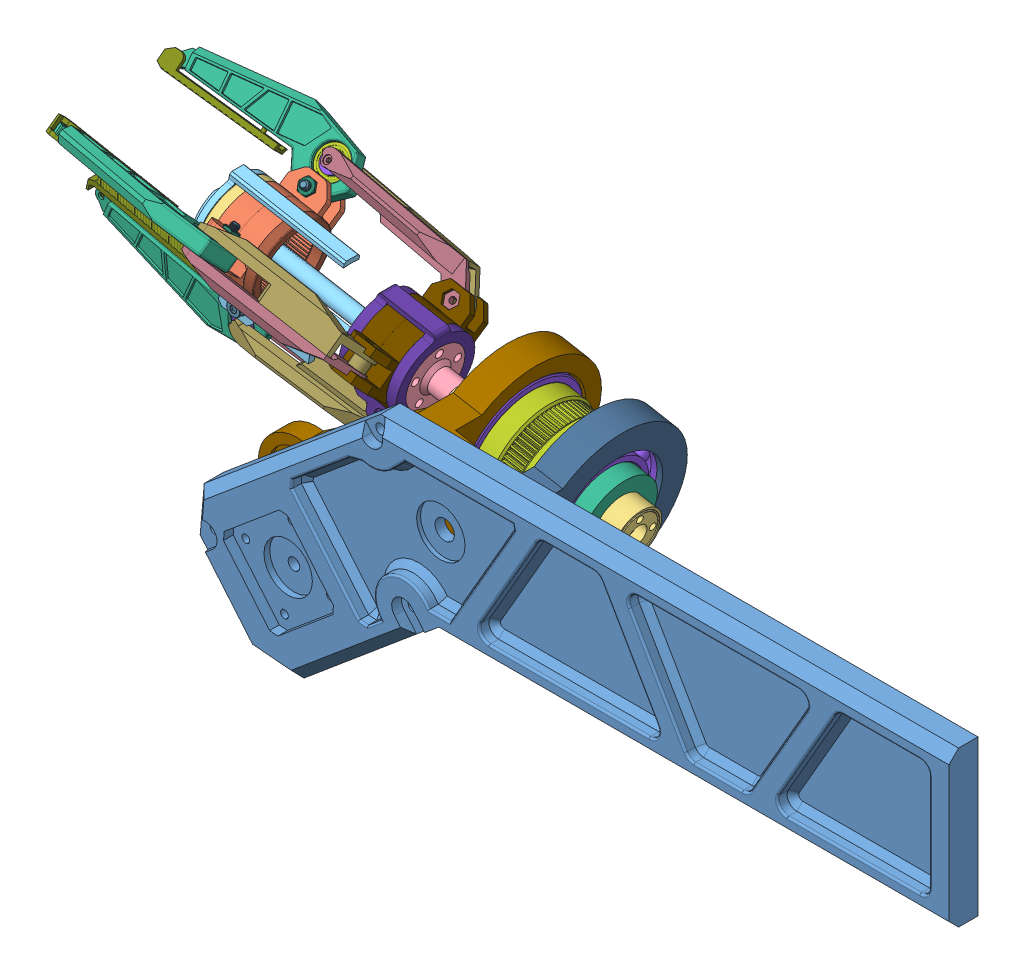
SolidWorks assembly AJ1, configuration Default. Lengths in mm.
Overall size (510.26 191.88 118.53).
61 component instances, 30 part files, 5 mates.
Components (placement in the parent):
- UpperSec-1: UpperSec [Default] at (34.476 163.0285 299.7549) size (391.25 137.61 15.09)
- CrawAssemV1.2-1: CrawAssemV1.2 [EX2] at (-53.1663 200.1756 226.5593) x (0.002865 0.01582 0.999871) z (-0.984 0.178167 0) size (105.21 107.56 278.95)
  - CrawPivotL-1: CrawPivotL [Default] at (23.6534 28.2906 36.4169) x (0.675201 -0.737634 0) z (0 0 1) size (40 51.64 20.02)
  - RotorInner-1: RotorInner [Default] at (23.6534 28.2906 51.4169) x (-0.675201 0.737634 0) z (0 0 -1) size (40 40 22.5)
  - 4668K131_Permanently Lubricated Stainless Steel Ball Bearing-1: 4668K131_Permanently Lubricated Stainless Steel Ball Bearing [4668K131] at (23.6534 28.2906 52.4169) x (0.977927 0.208948 0) z (0 0 1) size (16 16 4)
  - RotorOutter-1: RotorOutter [Default] at (23.6534 28.2906 56.4169) x (-0.999871 0.016078 0) z (0 0 -1) size (40 57.1 62)
  - CrawPivotL-2: CrawPivotL [Default] at (23.6534 28.2906 36.4169) x (-0.716673 -0.697409 0) z (0 0 -1) size (40 51.64 20.02)
  - FrontCraw-1: FrontCraw [Default] at (-7.9204 40.6623 113.525) x (-0.024761 0.025445 -0.99937) z (0.69697 -0.716221 -0.035504) size (92.48 8.06 30.71)
  - FrontCraw-2: FrontCraw [Default] at (49.7643 43.7862 113.4714) x (0.035168 0.032192 -0.998863) z (-0.736795 -0.674433 -0.047677) size (92.48 8.06 30.71)
  - 4668K334_Permanently Lubricated Stainless Steel Ball Bearing-1: 4668K334_Permanently Lubricated Stainless Steel Ball Bearing [4668K334] at (58.2277 46.2461 36.989) x (0.461728 0.422648 0.779857) z (-0.675201 0.737634 0) size (16 16 5)
  - BearingStop1-1: BearingStop1 [Default] at (56.5397 48.0902 36.989) x (-0.727461 -0.665889 0.165503) z (0.675201 -0.737634 0) size (10 10 6.25)
  - 4668K334_Permanently Lubricated Stainless Steel Ball Bearing-2: 4668K334_Permanently Lubricated Stainless Steel Ball Bearing [4668K334] at (-9.9873 48.3784 36.952) x (0.471273 -0.484291 0.737132) z (-0.716673 -0.697409 0) size (16 16 5)
  - BearingStop1-2: BearingStop1 [Default] at (-11.779 46.6349 36.952) x (-0.683695 0.702579 -0.197341) z (0.716673 0.697409 0) size (10 10 6.25)
  - BearingStop2-1: BearingStop2 [Default] at (55.6957 49.0123 36.989) x (-0.727461 -0.665889 0.165503) z (0.675201 -0.737634 0) size (10 10 7.25)
  - BearingStop2-2: BearingStop2 [Default] at (-12.6749 45.7632 36.952) x (-0.683695 0.702579 -0.197341) z (0.716673 0.697409 0) size (10 10 7.25)
  - FrontCraw-3: FrontCraw [Default] at (27.1452 -3.3521 113.4714) x (-0.000767 -0.047671 -0.998863) z (0.016059 0.998734 -0.047677) size (92.48 8.06 30.71)
  - 7804K117_Stainless Steel Ball Bearing-1: 7804K117_Stainless Steel Ball Bearing [7804K117] at (23.1186 -11.1922 36.989) x (-0.007051 -0.438494 -0.898707) z (0.999871 -0.016078 0) size (16 16 5)
  - BearingStop2-3: BearingStop2 [Default] at (19.3691 -11.1319 36.989) x (0.016038 0.997394 0.070343) z (0.999871 -0.016078 0) size (10 10 7.25)
  - BearingStop1-3: BearingStop1 [Default] at (20.6189 -11.152 36.989) x (0.016038 0.997394 0.070343) z (0.999871 -0.016078 0) size (10 10 6.25)
  - RotorInnerBack-1: RotorInnerBack [Default] at (23.6534 28.2906 21.4169) x (0.962311 -0.271952 0) z (0 0 1) size (40 40 8)
  - SEC2pull1-1: SEC2pull1 [Default] at (-10.6231 40.787 37.118) x (0.023165 -0.023805 -0.999448) z (0.716673 0.697409 0) size (85.51 19.7 15)
  - SEC2pull2-1: SEC2pull2 [Default] at (-3.4564 47.7611 37.118) x (0.023165 -0.023805 -0.999448) z (0.716673 0.697409 0) size (85.51 19.7 8.5)
  - 91290A164_Black-Oxide Alloy Steel Socket Head Screw-1: 91290A164_Black-Oxide Alloy Steel Socket Head Screw [91290A164] at (23.2113 0.7942 36.4169) x (0.000258 0.016076 -0.999871) z (0.999871 -0.016078 0) size (7 7 22.3)
  - 90592A090_Steel Hex Nut (1)-1: 90592A090_Steel Hex Nut (1) [90592A090] at (14.6124 0.9324 36.4169) x (0.016078 0.999871 0) z (0 0 1) size (7 3.75 8.08)
  - 91290A164_Black-Oxide Alloy Steel Socket Head Screw-2: 91290A164_Black-Oxide Alloy Steel Socket Head Screw [91290A164] at (-0.6785 40.3897 36.4169) x (-0.0003 0.000308 -1) z (-0.716673 -0.697409 0) size (7 7 22.3)
  - 90592A090_Steel Hex Nut (1)-2: 90592A090_Steel Hex Nut (1) [90592A090] at (4.0516 44.9926 36.4169) x (-0.348705 0.358336 -0.866025) z (-0.603974 0.620657 0.5) size (7 3.75 8.08)
  - 91290A164_Black-Oxide Alloy Steel Socket Head Screw-3: 91290A164_Black-Oxide Alloy Steel Socket Head Screw [91290A164] at (48.6435 38.9643 36.4169) x (-0.209995 -0.192222 0.95862) z (0.675201 -0.737634 0) size (7 7 22.3)
  - 90592A090_Steel Hex Nut (1)-3: 90592A090_Steel Hex Nut (1) [90592A090] at (44.1872 43.8327 36.4169) x (-0.368817 -0.3376 -0.866025) z (-0.63881 -0.584741 0.5) size (7 3.75 8.08)
  - UpperSecCraw (1)-1: UpperSecCraw (1) [Default] at (-7.216 44.2401 113.6369) x (-0.024761 0.025445 -0.99937) z (0.716673 0.697409 0) size (60.97 9.37 8)
  - UpperSecCraw (1)-2: UpperSecCraw (1) [Default] at (24.1122 -5.3749 113.6086) x (-0.000767 -0.047671 -0.998863) z (-0.999871 0.016078 0) size (60.97 9.37 8)
  - UpperSecCraw (1)-3: UpperSecCraw (1) [Default] at (53.3178 42.9719 113.6086) x (0.035168 0.032192 -0.998863) z (0.675201 -0.737634 0) size (60.97 9.37 8)
  - RTL-1: RTL [Default] at (23.6534 28.2906 -18.4955) x (-0.999871 0.016078 0) z (0 0 -1) size (40 56.1 30)
  - PullPivot-1: PullPivot [Default] at (23.6534 28.2906 -38.4955) x (0.675201 -0.737634 0) z (0 0 1) size (40 51.64 20)
  - 5972K213_Ball Bearing-1: 5972K213_Ball Bearing [5972K213] at (23.6534 28.2906 -33.4955) size (24 24 5)
  - PullPivot2-1: PullPivot2 [Default] at (23.6534 28.2906 -38.4955) x (0.999025 -0.044147 0) z (0 0 1) size (35 35 2.74)
  - PullPivot-2: PullPivot [Default] at (23.6534 28.2906 -38.4955) x (-0.716673 -0.697409 0) z (0 0 -1) size (40 51.64 20)
  - 5972K213_Ball Bearing-2: 5972K213_Ball Bearing [5972K213] at (23.6534 28.2906 -43.4955) x (0.923728 0.383049 0) z (0 0 -1) size (24 24 5)
  - PullPivot2-2: PullPivot2 [Default] at (23.6534 28.2906 -38.4955) x (-0.716673 -0.697409 0) z (0 0 -1) size (35 35 2.74)
  - SEC2pull1-2: SEC2pull1 [Default] at (50.6589 47.1131 37.1398) x (-0.022244 -0.020361 -0.999545) z (0.675201 -0.737634 0) size (85.51 19.7 15)
  - SEC2pull1-3: SEC2pull1 [Default] at (29.1982 -6.2916 37.1398) x (0.000485 0.030152 -0.999545) z (-0.999871 0.016078 0) size (85.51 19.7 15)
  - SEC2pull2-2: SEC2pull2 [Default] at (19.5494 -6.1365 37.1398) x (0.000485 0.030152 -0.999545) z (-0.999871 0.016078 0) size (85.51 19.7 8.5)
  - SEC2pull2-3: SEC2pull2 [Default] at (57.4109 39.7367 37.1398) x (-0.022244 -0.020361 -0.999545) z (0.675201 -0.737634 0) size (85.51 19.7 8.5)
  - CylinderTube-1: CylinderTube [Default] at (23.6534 28.2906 -74.2503) x (-0.999871 0.016078 0) z (-0.016078 -0.999871 0) size (35 85 35)
  - Hydro2-1: Hydro2 [Default] at (23.6534 28.2906 -50.4955) x (-0.999871 0.016078 0) z (0 0 -1) size (30 30 73)
  - 6112K44_Linear Motion Shaft-1: 6112K44_Linear Motion Shaft [6112K44] at (23.6534 28.2906 -52.5831) x (-0.201275 -0.979535 0) z (0 0 1) size (8 8 100)
  - Cylinder40mmCover-1: Cylinder40mmCover [Default] at (23.6534 28.2906 -79.2503) x (-0.999871 0.016078 0) z (0 0 -1) size (40 40 70)
  - PiV1-1: PiV1 [Default] at (23.6534 28.2906 -129.2503) x (0.999871 -0.016078 0) z (0 0 1) size (55 55 30)
  - PiVEnclosure1-1: PiVEnclosure1 [Default] at (23.6534 28.2906 -109.2503) x (0.791208 -0.611547 0) z (0 0 1) size (75 75 13) (hidden)
  - 4668K334_Permanently Lubricated Stainless Steel Ball Bearing-3: 4668K334_Permanently Lubricated Stainless Steel Ball Bearing [4668K334] at (19.2674 62.5359 -106.7503) size (16 16 5) (hidden)
  - 4668K334_Permanently Lubricated Stainless Steel Ball Bearing-4: 4668K334_Permanently Lubricated Stainless Steel Ball Bearing [4668K334] at (-10.5918 23.9046 -106.7503) size (16 16 5) (hidden)
  - 4668K334_Permanently Lubricated Stainless Steel Ball Bearing-5: 4668K334_Permanently Lubricated Stainless Steel Ball Bearing [4668K334] at (28.0395 -5.9546 -106.7503) size (16 16 5) (hidden)
  - 4668K334_Permanently Lubricated Stainless Steel Ball Bearing-6: 4668K334_Permanently Lubricated Stainless Steel Ball Bearing [4668K334] at (57.8987 32.6767 -106.7503) size (16 16 5) (hidden)
  - 5972K249_Ball Bearing-1: 5972K249_Ball Bearing [5972K249] at (23.6534 28.2906 -93.2503) x (0.88466 0.466238 0) z (0 0 1) size (62 62 12)
  - 5972K249_Ball Bearing-2: 5972K249_Ball Bearing [5972K249] at (23.6534 28.2906 -135.2503) x (0.910111 -0.414364 0) z (0 0 1) size (62 62 12)
- PiVyAxis-1: PiVyAxis [Default] at (137.0869 121.2307 219.8994) x (0 0 1) z (-0.984 0.178167 0) size (90 95.96 126.21)
  - PiVRing-1: PiVRing [Default] at (-10.1445 32.4522 102.0243) size (90 95.96 109.96)
  - 5972K249_Ball Bearing-1: 5972K249_Ball Bearing [5972K249] at (29.8555 72.4522 108.2243) x (0.455975 -0.889993 0) z (0 0 1) size (62 62 12) (hidden)
  - PiVRing2-1: PiVRing2 [Default] at (69.8555 32.4522 72.0243) x (-1 0 0) z (0 0 -1) size (90 80 20.25)
  - 92010A328_Passivated 18-8 Stainless Steel Phillips Flat Head Screw-1: 92010A328_Passivated 18-8 Stainless Steel Phillips Flat Head Screw [92010A328] at (74.8555 87.4522 67.6243) x (0.998285 -0.05854 0) z (0 0 -1) size (9.2 9.2 20.12)
  - 92010A328_Passivated 18-8 Stainless Steel Phillips Flat Head Screw-2: 92010A328_Passivated 18-8 Stainless Steel Phillips Flat Head Screw [92010A328] at (74.8555 57.4522 67.6243) x (1 0 0) z (0 0 -1) size (9.2 9.2 20.12)
  - 5972K249_Ball Bearing-2: 5972K249_Ball Bearing [5972K249] at (29.8555 72.4522 66.0243) size (62 62 12) (hidden)
Mates (geometry in assembly coordinates):
- Parallel1: parallel anti-aligned: plane of UpperSec-1 through (34.476 163.0285 299.7549) normal (0 0 -1); plane of CrawAssemV1.2-1/CylinderTube-1 through (26.8056 197.0444 267.2549) normal (0 0 1)
- Concentric1: concentric anti-aligned: cylinder of CrawAssemV1.2-1/5972K249_Ball Bearing-2 through (79.1236 205.356 249.7549) axis (-0.984 0.178167 0) radius 31; cylinder of PiVyAxis-1/PiVRing2-1 through (79.1236 205.356 249.7549) axis (0.984 -0.178167 0) radius 32
- Coincident1: coincident anti-aligned: plane of CrawAssemV1.2-1/5972K249_Ball Bearing-2 through (95.8965 230.6385 261.9051) normal (0.984 -0.178167 0); plane of PiVyAxis-1/PiVRing2-1 through (90.9316 203.218 249.7549) normal (-0.984 0.178167 0)
- Coincident2: coincident anti-aligned: plane of UpperSec-1 through (34.476 163.0285 299.7549) normal (0 0 -1); plane of PiVyAxis-1/PiVRing-1 through (42.4769 171.341 299.7549) normal (0 0 1)
- Concentric8: concentric aligned: cylinder of UpperSec-1 through (64.3636 208.0285 299.7549) axis (0 0 1) radius 5; cylinder of PiVyAxis-1/PiVRing-1 through (64.3636 208.0285 289.7549) axis (0 0 1) radius 4
